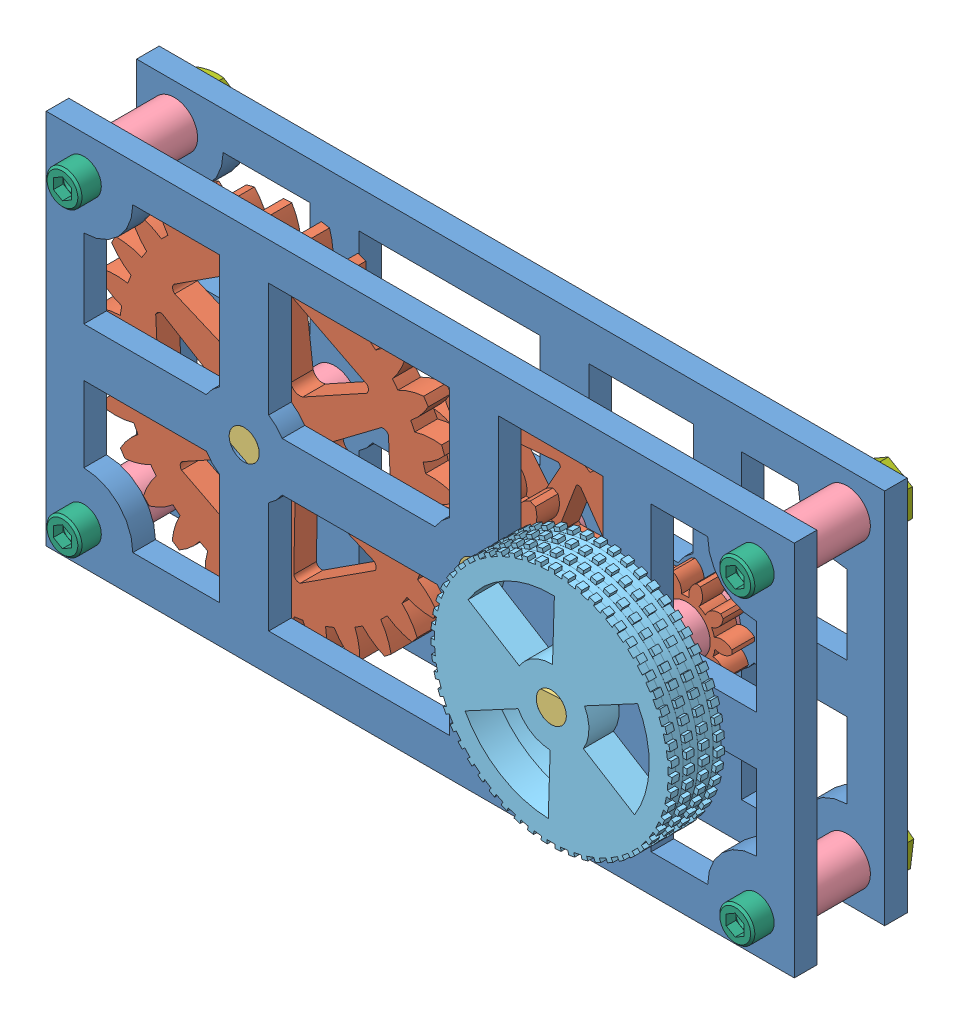
SolidWorks assembly finalAssem, configuration Default. Lengths in mm.
Overall size (105.29 64.44 29.05).
32 component instances, 7 part files, 38 mates.
Components (placement in the parent):
- plate-3: plate [Default] at (15.8282 -43.4601 104.4922) size (99.33 50 3)
- thirdShaft-3: thirdShaft [Default] at (16.0964 -36.3639 98.7516) x (-0.890453 0.455076 0) z (0 0 1) size (48 47.84 15)
  - root_gear-1: root_gear [30T 1.5Mod] at (24.7057 20.8305 13.7406) size (48 47.84 3)
  - axle-1: axle [15mm tall] at (24.7057 20.8305 20.7406) size (4 3.5 15)
  - spacer-1: spacer [5mm tall] at (24.7057 20.8305 8.7406) size (6.2 6.2 5)
  - spacer-2: spacer [1mm tall] at (24.7057 20.8305 16.7406) size (6.2 6.2 1)
- secondShaft-1: secondShaft [Default] at (4.6314 -43.2964 80.0269) x (-0.422432 -0.906395 0) z (0 0 1) size (32 31.89 15)
  - root_gear-1: root_gear [30T 1.0Mod] at (-4.2891 9.5907 28.4653) size (32 31.89 3)
  - root_gear-2: root_gear [10T 1.5Mod] at (-4.2891 9.5907 32.4653) size (18 17.34 3)
  - axle-1: axle [15mm tall] at (-4.2891 9.5907 39.4653) size (4 3.5 15)
  - spacer-1: spacer [1mm tall] at (-4.2891 9.5907 35.4653) size (6.2 6.2 1)
  - spacer-2: spacer [1mm tall] at (-4.2891 9.5907 27.4653) size (6.2 6.2 1)
  - spacer-3: spacer [1mm tall] at (-4.2891 9.5907 31.4653) size (6.2 6.2 1)
- inputShaft-1: inputShaft [Default] at (41.9288 -50.7772 123.5101) x (-0.998515 -0.054483 0) z (0 0 -1) size (12 11.56 25)
  - axle-1: axle [25mm tall] at (6.1264 7.6622 19.0178) size (4 3.5 25)
  - spacer-1: spacer [1mm tall] at (6.1264 7.6622 15.0178) size (6.2 6.2 1)
  - root_gear-1: root_gear [10T 1.0Mod] at (6.1264 7.6622 12.0178) size (12 11.56 3)
  - spacer-2: spacer [5mm tall] at (6.1264 7.6622 12.0178) x (-0.850804 -0.525483 0) z (0 0 -1) size (6.2 6.2 5)
- knob-1: knob [Default] at (35.394 -43.4601 129.4922) x (0 0 -1) z (0.031165 0.999514 0) size (7 32 32)
- plate-4: plate [Default] at (15.8282 -43.4601 116.4922) size (99.33 50 3)
- socket head cap screw_ai-2: socket head cap screw_ai [HX-SHCS 0.112-48x0.75x0.75-N] at (-36.6718 -63.4601 122.337) x (0 0 -1) z (1 0 0) size (21.89 4.65 4.65)
- socket head cap screw_ai-3: socket head cap screw_ai [HX-SHCS 0.112-48x0.75x0.75-N] at (-36.6718 -23.4601 122.337) x (0 0 -1) z (1 0 0) size (21.89 4.65 4.65)
- socket head cap screw_ai-4: socket head cap screw_ai [HX-SHCS 0.112-48x0.75x0.75-N] at (52.654 -23.4601 122.337) x (0 0 -1) z (1 0 0) size (21.89 4.65 4.65)
- socket head cap screw_ai-5: socket head cap screw_ai [HX-SHCS 0.112-48x0.75x0.75-N] at (52.654 -63.4601 122.337) x (0 0 -1) z (1 0 0) size (21.89 4.65 4.65)
- machine screw nut hex_ai-2: machine screw nut hex_ai [MSHXNUT 0.112-40-S-N] at (-36.6718 -63.4601 102.003) x (0.923728 0.383049 0) z (0 0 -1) size (6.35 7.33 2.49)
- machine screw nut hex_ai-3: machine screw nut hex_ai [MSHXNUT 0.112-40-S-N] at (-36.6718 -23.4601 102.003) x (-0.785956 -0.618282 0) z (0 0 -1) size (6.35 7.33 2.49)
- machine screw nut hex_ai-4: machine screw nut hex_ai [MSHXNUT 0.112-40-S-N] at (52.654 -23.4601 104.4922) size (6.35 7.33 2.49)
- machine screw nut hex_ai-5: machine screw nut hex_ai [MSHXNUT 0.112-40-S-N] at (52.654 -63.4601 104.4922) x (0.992202 -0.124641 0) z (0 0 1) size (6.35 7.33 2.49)
- spacer-2: spacer [9mm tall] at (52.654 -23.4601 107.4922) x (0.929403 0.369067 0) z (0.369067 -0.929403 0) size (6.2 9 6.2)
- spacer-3: spacer [9mm tall] at (52.654 -63.4601 116.4922) x (-0.235685 -0.971829 0) z (0.971829 -0.235685 0) size (6.2 9 6.2)
- spacer-4: spacer [9mm tall] at (-36.6718 -63.4601 116.4922) x (-0.235685 -0.971829 0) z (0.971829 -0.235685 0) size (6.2 9 6.2)
- spacer-5: spacer [9mm tall] at (-36.6718 -23.4601 116.4922) x (-0.235685 -0.971829 0) z (0.971829 -0.235685 0) size (6.2 9 6.2)
Mates (geometry in assembly coordinates):
- Concentric1: concentric aligned: cylinder of plate-3 through (-15.3823 -43.6696 104.4922) axis (0 0 1) radius 2; cylinder of thirdShaft-3/axle-1 through (-15.3823 -43.6696 104.4922) axis (0 0 1) radius 2
- Coincident3: coincident anti-aligned: plane of plate-3 through (15.8282 -43.4601 107.4922) normal (0 0 1); plane of thirdShaft-3/spacer-1 through (-15.3823 -43.6696 107.4922) normal (0 0 -1)
- Coincident6: coincident anti-aligned: plane of plate-3 through (15.8282 -43.4601 107.4922) normal (0 0 1); plane of secondShaft-1/spacer-2 through (15.1362 -43.4601 107.4922) normal (0 0 -1)
- Concentric2: concentric aligned: cylinder of plate-3 through (15.1362 -43.4601 97.4922) axis (0 0 1) radius 2; cylinder of secondShaft-1/axle-1 through (15.1362 -43.4601 104.4922) axis (0 0 1) radius 2
- Coincident9: coincident anti-aligned: plane of plate-3 through (15.8282 -43.4601 107.4922) normal (0 0 1); plane of inputShaft-1/spacer-1 through (35.394 -43.4601 107.4922) normal (0 0 -1)
- Concentric3: concentric anti-aligned: cylinder of plate-3 through (35.394 -43.4601 97.4922) axis (0 0 1) radius 2; cylinder of inputShaft-1/axle-1 through (35.394 -43.4601 129.4922) axis (0 0 -1) radius 2
- GearMate1: gear = 15 : 45 mm: cylinder of thirdShaft-3/root_gear-1 through (-15.3823 -43.6696 112.4922) axis (0 0 1) radius 20.625; cylinder of secondShaft-1/root_gear-2 through (15.1362 -43.4601 112.4922) axis (0 0 1) radius 5.625
- GearMate2: gear = 10 : 30 mm: cylinder of secondShaft-1/root_gear-1 through (15.1362 -43.4601 108.4922) axis (0 0 1) radius 13.75; cylinder of inputShaft-1/root_gear-1 through (35.394 -43.4601 111.4922) axis (0 0 -1) radius 3.75
- Concentric5: concentric anti-aligned: cylinder of inputShaft-1/axle-1 through (35.394 -43.4601 129.4922) axis (0 0 -1) radius 2; cylinder of knob-1 through (35.394 -43.4601 129.4922) axis (0 0 1) radius 2
- Coincident10: coincident aligned: plane of inputShaft-1/axle-1 through (35.394 -43.4601 129.4922) normal (0 0 1); plane of knob-1 through (34.8954 -59.4524 129.4922) normal (0 0 1)
- Parallel2: parallel aligned: plane of inputShaft-1/axle-1 through (33.9914 -42.0344 129.4922) normal (-0.054483 0.998515 0); plane of knob-1 through (35.0488 -27.9559 119.4922) normal (-0.054483 0.998515 0)
- Concentric6: concentric aligned: cylinder of thirdShaft-3/axle-1 through (-15.3823 -43.6696 104.4922) axis (0 0 1) radius 2; cylinder of plate-4 through (-15.3823 -43.6696 116.4922) axis (0 0 1) radius 2
- Coincident12: coincident aligned: plane of thirdShaft-3/axle-1 through (-15.3823 -43.6696 119.4922) normal (0 0 1); plane of plate-4 through (15.8282 -43.4601 119.4922) normal (0 0 1)
- Concentric7: concentric aligned: cylinder of secondShaft-1/axle-1 through (15.1362 -43.4601 104.4922) axis (0 0 1) radius 2; cylinder of plate-4 through (15.1362 -43.4601 109.4922) axis (0 0 1) radius 2
- Concentric10: concentric aligned: cylinder of plate-4 through (-36.6718 -63.4601 116.4922) axis (0 0 1) radius 1.5; cylinder of socket head cap screw_ai-2 through (-36.6718 -63.4601 154.087) axis (0 0 1) radius 2.3241
- Coincident15: coincident anti-aligned: plane of plate-4 through (15.8282 -43.4601 119.4922) normal (0 0 1); plane of socket head cap screw_ai-2 through (-36.6718 -61.136 119.4922) normal (0 0 -1)
- Concentric11: concentric aligned: cylinder of plate-4 through (-36.6718 -23.4601 116.4922) axis (0 0 1) radius 1.5; cylinder of socket head cap screw_ai-3 through (-36.6718 -23.4601 154.087) axis (0 0 1) radius 2.3241
- Coincident16: coincident anti-aligned: plane of plate-4 through (15.8282 -43.4601 119.4922) normal (0 0 1); plane of socket head cap screw_ai-3 through (-36.6718 -21.136 119.4922) normal (0 0 -1)
- Concentric12: concentric aligned: cylinder of plate-4 through (52.654 -23.4601 116.4922) axis (0 0 1) radius 1.5; cylinder of socket head cap screw_ai-4 through (52.654 -23.4601 154.087) axis (0 0 1) radius 2.3241
- Coincident17: coincident anti-aligned: plane of plate-4 through (15.8282 -43.4601 119.4922) normal (0 0 1); plane of socket head cap screw_ai-4 through (52.654 -21.136 119.4922) normal (0 0 -1)
- Concentric13: concentric aligned: cylinder of plate-4 through (52.654 -63.4601 116.4922) axis (0 0 1) radius 1.5; cylinder of socket head cap screw_ai-5 through (52.654 -63.4601 154.087) axis (0 0 1) radius 2.3241
- Coincident18: coincident anti-aligned: plane of plate-4 through (15.8282 -43.4601 119.4922) normal (0 0 1); plane of socket head cap screw_ai-5 through (52.654 -61.136 119.4922) normal (0 0 -1)
- Concentric14: concentric aligned: cone of socket head cap screw_ai-2 through (-36.6718 -63.4601 100.4422) axis (0 0 -1); cylinder of machine screw nut hex_ai-2 through (-36.6718 -63.4601 127.0405) axis (0 0 -1) radius 1.4224
- Concentric15: concentric aligned: cone of socket head cap screw_ai-3 through (-36.6718 -23.4601 100.4422) axis (0 0 -1); cylinder of machine screw nut hex_ai-3 through (-36.6718 -23.4601 127.0405) axis (0 0 -1) radius 1.4224
- Concentric16: concentric aligned: cylinder of socket head cap screw_ai-4 through (52.654 -23.4601 154.087) axis (0 0 1) radius 1.4224; cylinder of machine screw nut hex_ai-4 through (52.654 -23.4601 79.4547) axis (0 0 1) radius 1.4224
- Concentric17: concentric aligned: cylinder of socket head cap screw_ai-5 through (52.654 -63.4601 154.087) axis (0 0 1) radius 1.4224; cylinder of machine screw nut hex_ai-5 through (52.654 -63.4601 79.4547) axis (0 0 1) radius 1.4224
- Coincident23: coincident anti-aligned: plane of plate-3 through (15.8282 -43.4601 104.4922) normal (0 0 -1); plane of machine screw nut hex_ai-3 through (-38.9386 -20.5787 104.4922) normal (0 0 1)
- Coincident24: coincident anti-aligned: plane of plate-3 through (15.8282 -43.4601 104.4922) normal (0 0 -1); plane of machine screw nut hex_ai-2 through (-35.2675 -66.8467 104.4922) normal (0 0 1)
- Coincident25: coincident anti-aligned: plane of plate-3 through (15.8282 -43.4601 104.4922) normal (0 0 -1); plane of machine screw nut hex_ai-5 through (53.111 -59.8226 104.4922) normal (0 0 1)
- Coincident26: coincident anti-aligned: plane of plate-3 through (15.8282 -43.4601 104.4922) normal (0 0 -1); plane of machine screw nut hex_ai-4 through (52.654 -19.794 104.4922) normal (0 0 1)
- Concentric18: concentric anti-aligned: cylinder of socket head cap screw_ai-4 through (52.654 -23.4601 154.087) axis (0 0 1) radius 1.4224; cylinder of spacer-2 through (52.654 -23.4601 116.4922) axis (0 0 -1) radius 1.425
- Coincident29: coincident anti-aligned: plane of plate-4 through (15.8282 -43.4601 116.4922) normal (0 0 -1); plane of spacer-2 through (52.654 -23.4601 116.4922) normal (0 0 1)
- Concentric191: concentric aligned: cylinder of socket head cap screw_ai-5 through (52.654 -63.4601 154.087) axis (0 0 1) radius 1.4224; cylinder of spacer-3 through (52.654 -63.4601 107.4922) axis (0 0 1) radius 3.1
- Coincident30: coincident anti-aligned: plane of plate-3 through (15.8282 -43.4601 107.4922) normal (0 0 1); plane of spacer-3 through (52.654 -63.4601 107.4922) normal (0 0 -1)
- Concentric221: concentric aligned: cylinder of socket head cap screw_ai-2 through (-36.6718 -63.4601 154.087) axis (0 0 1) radius 1.4224; cylinder of spacer-4 through (-36.6718 -63.4601 107.4922) axis (0 0 1) radius 3.1
- Coincident31: coincident anti-aligned: plane of plate-4 through (15.8282 -43.4601 116.4922) normal (0 0 -1); plane of spacer-4 through (-36.6718 -63.4601 116.4922) normal (0 0 1)
- Concentric231: concentric aligned: cylinder of socket head cap screw_ai-3 through (-36.6718 -23.4601 154.087) axis (0 0 1) radius 1.4224; cylinder of spacer-5 through (-36.6718 -23.4601 107.4922) axis (0 0 1) radius 3.1
- Coincident32: coincident anti-aligned: plane of plate-4 through (15.8282 -43.4601 116.4922) normal (0 0 -1); plane of spacer-5 through (-36.6718 -23.4601 116.4922) normal (0 0 1)
